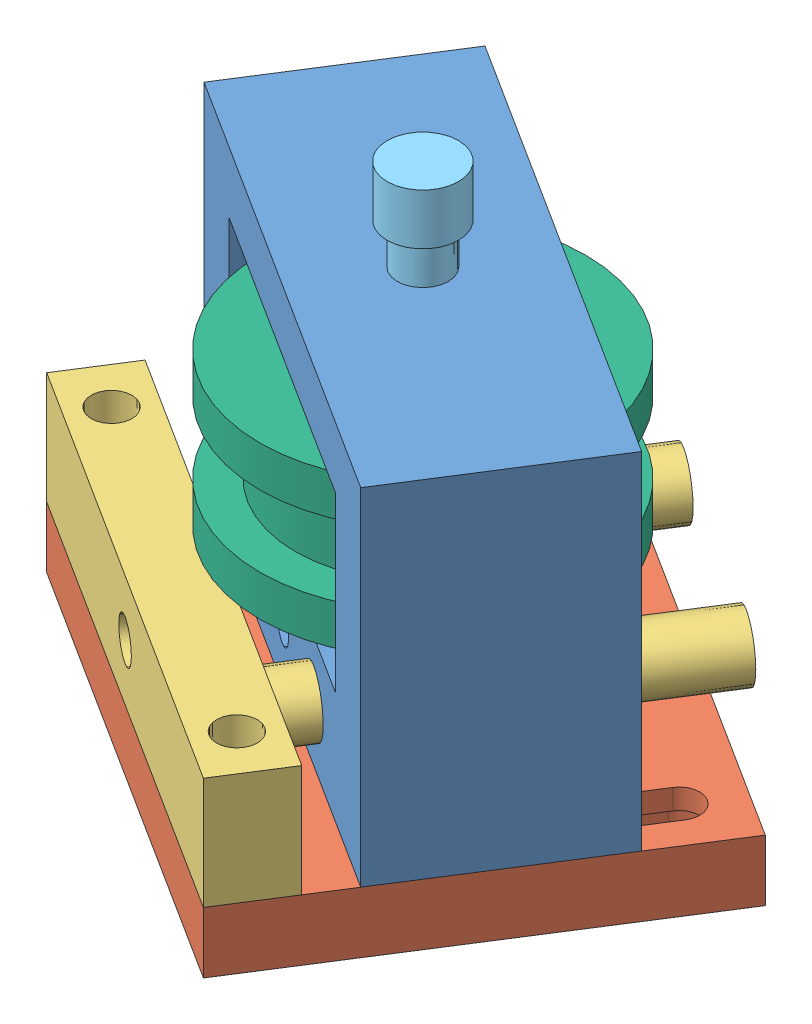
SolidWorks assembly BeltTensionerAssembly, configuration Default. Lengths in mm.
Overall size (64.72 49 62.26).
7 component instances, 6 part files, 23 mates.
Components (placement in the parent):
- SliderPlate-1: SliderPlate [Default] at (-6.0834 22.0445 41.5251) x (-0.8441 0 -0.536186) z (0 1 0) size (50 20 34)
- BasePlate-2: BasePlate [Default] at (-6.7261 16.0445 42.537) x (0.8441 0 0.536186) z (0 1 0) size (50 40 6)
- FrontFixed-2: FrontFixed [Default] at (-15.5732 22.0445 56.4646) x (0.8441 0 0.536186) z (0 1 0) size (50 42 11)
- washer-1: washer [Default] at (-6.0834 50.0445 41.5251) x (0 0 1) z (0 -1 0) size (8 8 1)
- washer-2: washer [Default] at (-6.0834 34.0445 41.5251) x (1 0 0) z (0 -1 0) size (8 8 1)
- M5x25-1: M5x25 [Default] at (-6.0834 65.0445 41.5251) x (0 -1 0) z (0 0 1) size (35 7 7)
- ideler-1: ideler [Default] at (-6.0834 49.0445 41.5251) x (0 -1 0) z (-1 0 0) size (15 32 32)
Mates (geometry in assembly coordinates):
- Coincident6: coincident aligned: plane of SliderPlate-1 through (-21.824 33.0445 19.6794) normal (-0.8441 0 -0.536186); plane of BasePlate-2 through (-38.5523 22.0445 46.0143) normal (-0.8441 0 -0.536186)
- Coincident7: coincident aligned: plane of FrontFixed-1 through (31.2709 17.198 59.1314) normal (0 0 1); plane of BasePlate-2 through (-38.5523 22.0445 46.0143) normal (-0.536186 0 0.8441)
- Coincident8: coincident anti-aligned: plane of SliderPlate-1 through (-6.0834 22.0445 41.5251) normal (0 -1 0); plane of BasePlate-2 through (-6.7261 22.0445 42.537) normal (0 1 0)
- Coincident12: coincident anti-aligned: plane of FrontFixed-1 through (6.2709 13.198 56.6314) normal (0 -1 0); plane of BasePlate-2 through (-6.7261 22.0445 42.537) normal (0 1 0)
- Coincident13: coincident anti-aligned: plane of BasePlate-2 through (-6.7261 22.0445 42.537) normal (0 1 0); plane of FrontFixed-2 through (-15.5732 22.0445 56.4646) normal (0 -1 0)
- Coincident14: coincident aligned: plane of BasePlate-2 through (-38.5523 22.0445 46.0143) normal (-0.536186 0 0.8441); plane of FrontFixed-2 through (-38.5523 33.0445 46.0143) normal (-0.536186 0 0.8441)
- Coincident15: coincident aligned: plane of BasePlate-2 through (3.6527 22.0445 72.8236) normal (0.8441 0 0.536186); plane of FrontFixed-2 through (3.6527 33.0445 72.8236) normal (0.8441 0 0.536186)
- Coincident16: coincident anti-aligned: plane of SliderPlate-1 through (-6.0834 33.0445 41.5251) normal (0 1 0); plane of washer-2 through (-6.0834 33.0445 41.5251) normal (0 -1 0)
- Tangent3: tangent: face of ?; plane of washer-1 through (-6.0834 49.0445 41.5251) normal (0 -1 0)
- Distance1: distance = 3 mm anti-aligned: plane of M5x25-1 through (-3.5834 30.0445 41.5251) normal (0 -1 0); plane of SliderPlate-1 through (-6.0834 33.0445 41.5251) normal (0 1 0)
- Coincident20: coincident anti-aligned: plane of SliderPlate-1 through (-6.0834 50.0445 41.5251) normal (0 -1 0); plane of washer-1 through (-6.0834 50.0445 41.5251) normal (0 1 0)
- Coincident21: coincident anti-aligned: circle of SliderPlate-1; cylinder of washer-1 through (-6.0834 49.0445 41.5251) axis (0 1 0) radius 2.5
- Coincident22: coincident anti-aligned: plane of SliderPlate-1 through (-6.0834 33.0445 41.5251) normal (0 1 0); circle of washer-2
- Coincident23: coincident anti-aligned: cylinder of SliderPlate-1 through (-6.0834 30.0445 41.5251) axis (0 1 0) radius 2.5; circle of washer-2
- Tangent4: tangent: edge_curve of ?; plane of washer-1 through (-6.0834 49.0445 41.5251) normal (0 -1 0)
- Tangent5: tangent: edge_curve of ?; cylinder of washer-1 through (-6.0834 49.0445 41.5251) axis (0 1 0) radius 2.5
- Concentric6: concentric aligned: cylinder of SliderPlate-1 through (-6.0834 42.9735 41.5251) axis (0 1 0) radius 2.5; cylinder of M5x25-1 through (-6.0834 65.0445 41.5251) axis (0 1 0) radius 2.5
- Coincident24: coincident anti-aligned: plane of washer-1 through (-6.0834 49.0445 41.5251) normal (0 -1 0); plane of ideler-2 through (-22.0834 49.0445 41.5251) normal (0 1 0)
- Concentric7: concentric anti-aligned: cylinder of M5x25-1 through (-6.0834 65.0445 41.5251) axis (0 1 0) radius 2.5; cylinder of ideler-2 through (-6.0834 56.257 41.5251) axis (0 -1 0) radius 2.55
- Concentric8: concentric aligned: cylinder of M5x25-1 through (-6.0834 65.0445 41.5251) axis (0 1 0) radius 2.5; cylinder of Pulley-1 through (-6.0834 21.1151 41.5251) axis (0 1 0) radius 2.5
- Coincident25: coincident anti-aligned: plane of SliderPlate-1 through (-6.0834 50.0445 41.5251) normal (0 -1 0); plane of Pulley-1 through (-6.0831 50.0445 41.525) normal (0 1 0)
- Coincident26: coincident anti-aligned: plane of washer-1 through (-6.0834 49.0445 41.5251) normal (0 -1 0); plane of ideler-1 through (-6.0834 49.0445 41.5251) normal (0 1 0)
- Concentric9: concentric aligned: cylinder of M5x25-1 through (-6.0834 65.0445 41.5251) axis (0 1 0) radius 2.5; cylinder of ideler-1 through (-6.0834 26.832 41.5251) axis (0 1 0) radius 2.55
